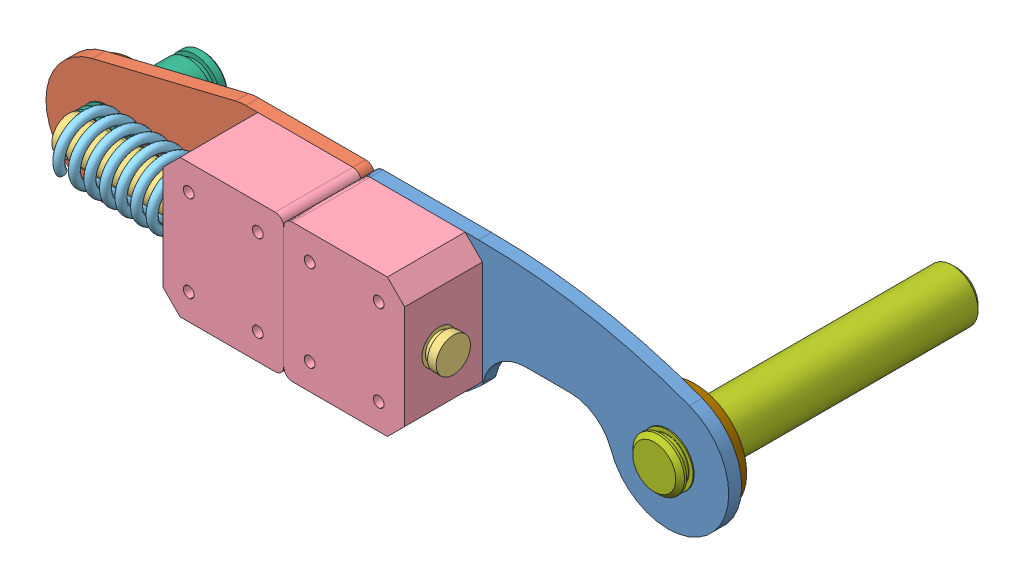
SolidWorks assembly Assem1-knee-mod1-hind, configuration Défaut. Lengths in mm.
Overall size (79.34 18.17 43.67).
14 component instances, 9 part files, 29 mates.
Components (placement in the parent):
- Part2-knee-mod3-hind-2: Part2-knee-mod3-hind [Défaut] at (3.122 0.7472 0) size (42.52 18.02 1.5)
- Part1-knee-mod3-hind-3: Part1-knee-mod3-hind [Défaut] at (-61.878 0.7472 0) x (-1 0 0) z (0 0 -1) size (36.52 18.02 1.5)
- part2-knee-mod1-1: part2-knee-mod1 [Default] at (-61.238 3.7472 5.75) x (0 -1 0) z (0 0 1) size (4 44.5 4)
- part4-knee-mod1-4: part4-knee-mod1 [Défaut] at (-25.378 3.7472 5.75) x (0 -1 0) z (1 0 0) size (16 9 14)
- Spring_DF-1670-2: Spring_DF-1670 [Défaut] at (-48.378 3.7472 5.75) x (0 0.257444 0.966293) z (-1 0 0) size (8.62 8.62 12.7)
- al_d6_1-1: al_d6_1 [Default] at (-61.878 0.7472 -10.41) x (1 0 0) z (0 -1 0) size (6 13 6)
- d5l35-2: d5l35 [Default] at (3.122 0.7472 -32.65) x (1 0 0) z (0 -1 0) size (6 35 6)
- part4-knee-mod1-7: part4-knee-mod1 [Défaut] at (-39.378 3.7472 5.75) x (0 1 0) z (-1 0 0) size (16 9 14)
- lock washer for shafts_din-3: lock washer for shafts_din [PreviewCfg] at (-59.598 3.7472 5.75) x (0 0.99885 0.047948) z (1 0 0) size (2.25 1.94 0.2)
- lock washer for shafts_din-4: lock washer for shafts_din [PreviewCfg] at (-18.378 3.7472 5.75) x (0 -1 0) z (-1 0 0) size (2.25 1.94 0.2)
- lock washer for shafts_din-5: lock washer for shafts_din [PreviewCfg] at (3.122 0.7472 1.05) size (2.25 1.94 0.2)
- lock washer for shafts_din-6: lock washer for shafts_din [PreviewCfg] at (-61.878 0.7472 1.05) size (2.25 1.94 0.2)
- Washer-d6p5-12-1: Washer-d6p5-12 [Défaut] at (3.122 0.7472 -1.55) x (-0.219521 -0.975608 0) z (0 0 1) size (12 12 1.6)
- Washer-d6p5-12-2: Washer-d6p5-12 [Défaut] at (-61.878 0.7472 -1.55) x (-0.219521 -0.975608 0) z (0 0 1) size (12 12 1.6)
Mates (geometry in assembly coordinates):
- Distance1: distance = 0 mm anti-aligned: plane of Part2-knee-mod3-hind-2 through (-32.378 11.7472 0.75) normal (-1 0 0); plane of Part1-knee-mod3-hind-3 through (-32.378 11.7472 -0.75) normal (1 0 0)
- Coïncidente2: coincident aligned: plane of Part2-knee-mod3-hind-2 through (3.122 0.7472 0.75) normal (0 0 1); plane of Part1-knee-mod3-hind-3 through (-61.878 0.7472 0.75) normal (0 0 1)
- Coaxiale19: concentric aligned: cylinder of part2-knee-mod1-1 through (-61.238 3.7472 5.75) axis (-1 0 0) radius 2; line of Spring_DF-1670-2 through (-48.378 3.7472 5.75) axis (-1 0 0)
- Coaxiale20: concentric anti-aligned: cylinder of Part1-knee-mod3-hind-3 through (-61.878 0.7472 -0.75) axis (0 0 1) radius 3.025; cylinder of al_d6_1-1 through (-61.878 0.7472 -10.41) axis (0 0 -1) radius 3
- Coaxiale21: concentric aligned: cylinder of Part2-knee-mod3-hind-2 through (3.122 0.7472 0.75) axis (0 0 -1) radius 3.025; cylinder of d5l35-2 through (3.122 0.7472 -32.65) axis (0 0 -1) radius 3
- Distance6: distance = 0.1 mm aligned: plane of al_d6_1-1 through (-61.878 3.2472 0.85) normal (0 0 1); plane of Part1-knee-mod3-hind-3 through (-61.878 0.7472 0.75) normal (0 0 1)
- Coïncidente21: coincident aligned: plane of al_d6_1-1 through (-61.878 3.2472 0.85) normal (0 0 1); plane of d5l35-2 through (3.122 4.3472 0.85) normal (0 0 1)
- Coïncidente22: coincident anti-aligned: plane of Part2-knee-mod3-hind-2 through (3.122 0.7472 0.75) normal (0 0 1); plane of part4-knee-mod1-4 through (-18.378 11.7472 0.75) normal (0 0 -1)
- Coaxiale22: concentric aligned: cylinder of Part2-knee-mod3-hind-2 through (-21.378 8.7472 0.75) axis (0 0 -1) radius 0.85; cylinder of part4-knee-mod1-4 through (-21.378 8.7472 0.75) axis (0 0 -1) radius 0.625
- Coaxiale23: concentric aligned: cylinder of Part2-knee-mod3-hind-2 through (-21.378 -1.2528 0.75) axis (0 0 -1) radius 0.85; cylinder of part4-knee-mod1-4 through (-21.378 -1.2528 0.75) axis (0 0 -1) radius 0.625
- Coïncidente23: coincident aligned: plane of part2-knee-mod1-1 through (-18.378 1.5723 5.75) normal (1 0 0); plane of part4-knee-mod1-4 through (-18.378 11.7472 9.75) normal (1 0 0)
- Coïncidente26: coincident anti-aligned: plane of Part1-knee-mod3-hind-3 through (-61.878 0.7472 0.75) normal (0 0 1); plane of part4-knee-mod1-7 through (-46.378 -4.2528 0.75) normal (0 0 -1)
- Coaxiale28: concentric anti-aligned: cylinder of Part1-knee-mod3-hind-3 through (-43.378 -1.2528 -0.75) axis (0 0 1) radius 0.85; cylinder of part4-knee-mod1-7 through (-43.378 -1.2528 0.75) axis (0 0 -1) radius 0.625
- Coaxiale29: concentric anti-aligned: cylinder of Part1-knee-mod3-hind-3 through (-43.378 8.7472 -0.75) axis (0 0 1) radius 0.85; cylinder of part4-knee-mod1-7 through (-43.378 8.7472 0.75) axis (0 0 -1) radius 0.625
- Distance7: distance = 2 mm aligned: plane of Spring_DF-1670-2 through (-48.378 3.7472 5.75) normal (-1 0 0); plane of part4-knee-mod1-7 through (-46.378 -4.2528 9.75) normal (-1 0 0)
- Coïncidente29: coincident anti-aligned: plane of part2-knee-mod1-1 through (-59.598 2.1472 5.75) normal (-1 0 0); plane of lock washer for shafts_din-3 through (-59.598 3.7472 5.75) normal (1 0 0)
- Coaxiale31: concentric aligned: cylinder of part2-knee-mod1-1 through (-16.738 3.7472 5.75) axis (1 0 0) radius 1.6; cylinder of lock washer for shafts_din-3 through (-59.798 3.7472 5.75) axis (1 0 0) radius 0.4
- Coaxiale34: concentric anti-aligned: cylinder of part2-knee-mod1-1 through (-61.238 3.7472 5.75) axis (-1 0 0) radius 2; cylinder of part4-knee-mod1-7 through (-46.378 3.7472 5.75) axis (1 0 0) radius 2
- Coaxiale35: concentric anti-aligned: cylinder of part2-knee-mod1-1 through (-16.738 3.7472 5.75) axis (1 0 0) radius 1.6; cylinder of lock washer for shafts_din-4 through (-18.178 3.7472 5.75) axis (-1 0 0) radius 0.4
- Coïncidente30: coincident anti-aligned: plane of part2-knee-mod1-1 through (-18.378 1.5723 5.75) normal (1 0 0); plane of lock washer for shafts_din-4 through (-18.378 3.7472 5.75) normal (-1 0 0)
- Coïncidente31: coincident anti-aligned: plane of d5l35-2 through (3.122 4.3472 0.85) normal (0 0 1); plane of lock washer for shafts_din-5 through (3.122 0.7472 0.85) normal (0 0 -1)
- Coaxiale36: concentric anti-aligned: cylinder of d5l35-2 through (3.122 0.7472 17.35) axis (0 0 -1) radius 2.5; cylinder of lock washer for shafts_din-5 through (3.122 0.7472 0.85) axis (0 0 1) radius 0.4
- Coaxiale37: concentric anti-aligned: cylinder of al_d6_1-1 through (-61.878 0.7472 39.6188) axis (0 0 -1) radius 2.5; cylinder of lock washer for shafts_din-6 through (-61.878 0.7472 0.85) axis (0 0 1) radius 0.4
- Coïncidente32: coincident anti-aligned: plane of al_d6_1-1 through (-61.878 3.2472 0.85) normal (0 0 1); plane of lock washer for shafts_din-6 through (-61.878 0.7472 0.85) normal (0 0 -1)
- Coïncidente33: coincident aligned: plane of Part2-knee-mod3-hind-2 through (-32.378 11.7472 0.75) normal (0 1 0); plane of Part1-knee-mod3-hind-3 through (-32.378 11.7472 -0.75) normal (0 1 0)
- Concentric1: concentric aligned: cylinder of al_d6_1-1 through (-61.878 0.7472 -10.41) axis (0 0 -1) radius 3; cylinder of Washer-d6p5-12-2 through (-61.878 0.7472 -0.75) axis (0 0 -1) radius 3.25
- Concentric2: concentric aligned: cylinder of d5l35-2 through (3.122 0.7472 -32.65) axis (0 0 -1) radius 3; cylinder of Washer-d6p5-12-1 through (3.122 0.7472 -0.75) axis (0 0 -1) radius 3.25
- Coincident1: coincident anti-aligned: plane of Part1-knee-mod3-hind-3 through (-61.878 0.7472 -0.75) normal (0 0 -1); plane of Washer-d6p5-12-2 through (-61.878 0.7472 -0.75) normal (0 0 1)
- Coincident2: coincident anti-aligned: plane of Part2-knee-mod3-hind-2 through (3.122 0.7472 -0.75) normal (0 0 -1); plane of Washer-d6p5-12-1 through (3.122 0.7472 -0.75) normal (0 0 1)
